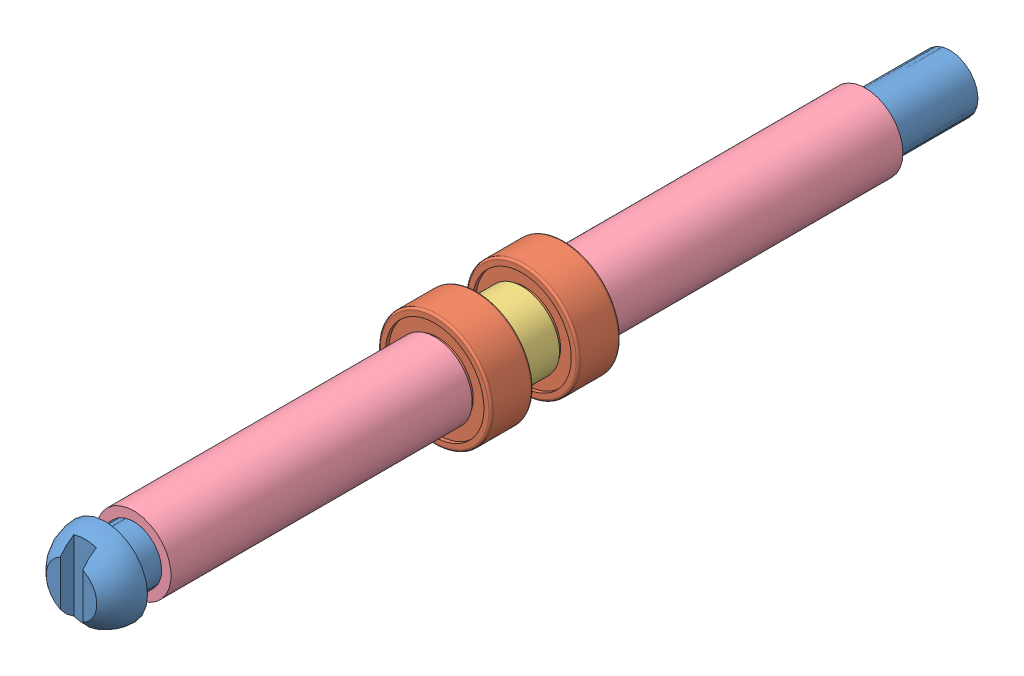
SolidWorks assembly Elevator_Front_Bearing_Assembly, configuration Default. Lengths in mm.
Overall size (17.82 17.82 99.06).
6 component instances, 4 part files, 10 mates.
Components (placement in the parent):
- .25-20 bolt-1: .25-20 bolt [Default] at (20.9022 42.2675 71.9832) size (9.53 9.53 99.06)
- Radial_Bearing_0.5_inch-1: Radial_Bearing_0.5_inch [Default] at (20.9022 42.2675 48.3294) x (0 0 -1) z (0.964421 -0.264372 0) size (4.76 12.7 12.7)
- Radial_Bearing_0.5_inch-2: Radial_Bearing_0.5_inch [Default] at (20.9022 42.2675 38.4869) x (0 0 -1) z (0.788975 0.614426 0) size (4.76 12.7 12.7)
- Spacer_0.2_inch-2: Spacer_0.2_inch [Default] at (20.9022 42.2675 40.8682) x (0.991317 0.131493 0) z (0 0 1) size (8.47 8.47 5.08)
- Spacer_inch-1: Spacer_inch [Default] at (20.9022 42.2675 50.7107) x (-0.955936 -0.293574 0) z (0 0 1) size (8.47 8.47 33.97)
- Spacer_inch-2: Spacer_inch [Default] at (20.9022 42.2675 2.1332) x (-0.332332 -0.943163 0) z (0 0 1) size (8.47 8.47 33.97)
Mates (geometry in assembly coordinates):
- Coincident5: coincident anti-aligned: plane of Radial_Bearing_0.5_inch-1 through (21.9514 46.0951 45.9482) normal (0 0 -1); plane of Spacer_0.2_inch-2 through (20.9022 42.2675 45.9482) normal (0 0 1)
- Coincident6: coincident anti-aligned: plane of Radial_Bearing_0.5_inch-2 through (18.8734 44.8727 40.8682) normal (0 0 1); plane of Spacer_0.2_inch-2 through (20.9022 42.2675 40.8682) normal (0 0 -1)
- Coincident7: coincident anti-aligned: plane of Radial_Bearing_0.5_inch-1 through (21.7752 45.4521 50.7107) normal (0 0 1); plane of Spacer_inch-1 through (20.9022 42.2675 50.7107) normal (0 0 -1)
- Coincident8: coincident anti-aligned: plane of Radial_Bearing_0.5_inch-2 through (18.4637 45.3988 36.1057) normal (0 0 -1); plane of Spacer_inch-2 through (20.9022 42.2675 36.1057) normal (0 0 1)
- Concentric6: concentric aligned: cylinder of Spacer_inch-1 through (20.9022 42.2675 84.6832) axis (0 0 -1) radius 3.175; cylinder of Spacer_inch-2 through (20.9022 42.2675 36.1057) axis (0 0 -1) radius 3.175
- Concentric7: concentric anti-aligned: cylinder of Radial_Bearing_0.5_inch-1 through (20.9022 42.2675 45.9469) axis (0 0 1) radius 3.175; cylinder of Spacer_inch-1 through (20.9022 42.2675 84.6832) axis (0 0 -1) radius 3.175
- Concentric8: concentric aligned: cylinder of Spacer_0.2_inch-2 through (20.9022 42.2675 45.9482) axis (0 0 -1) radius 3.175; cylinder of Spacer_inch-1 through (20.9022 42.2675 84.6832) axis (0 0 -1) radius 3.175
- Concentric9: concentric anti-aligned: cylinder of Radial_Bearing_0.5_inch-2 through (20.9022 42.2675 36.1044) axis (0 0 1) radius 3.175; cylinder of Spacer_inch-1 through (20.9022 42.2675 84.6832) axis (0 0 -1) radius 3.175
- Concentric10: concentric anti-aligned: cylinder of .25-20 bolt-1 through (20.9022 42.2675 -7.3918) axis (0 0 1) radius 3.175; cylinder of Spacer_inch-1 through (20.9022 42.2675 84.6832) axis (0 0 -1) radius 3.175
- Distance1: distance = 3.175 mm anti-aligned: plane of Spacer_inch-1 through (20.9022 42.2675 84.6832) normal (0 0 1); plane of .25-20 bolt-1 through (20.9022 42.2675 87.8582) normal (0 0 -1)
